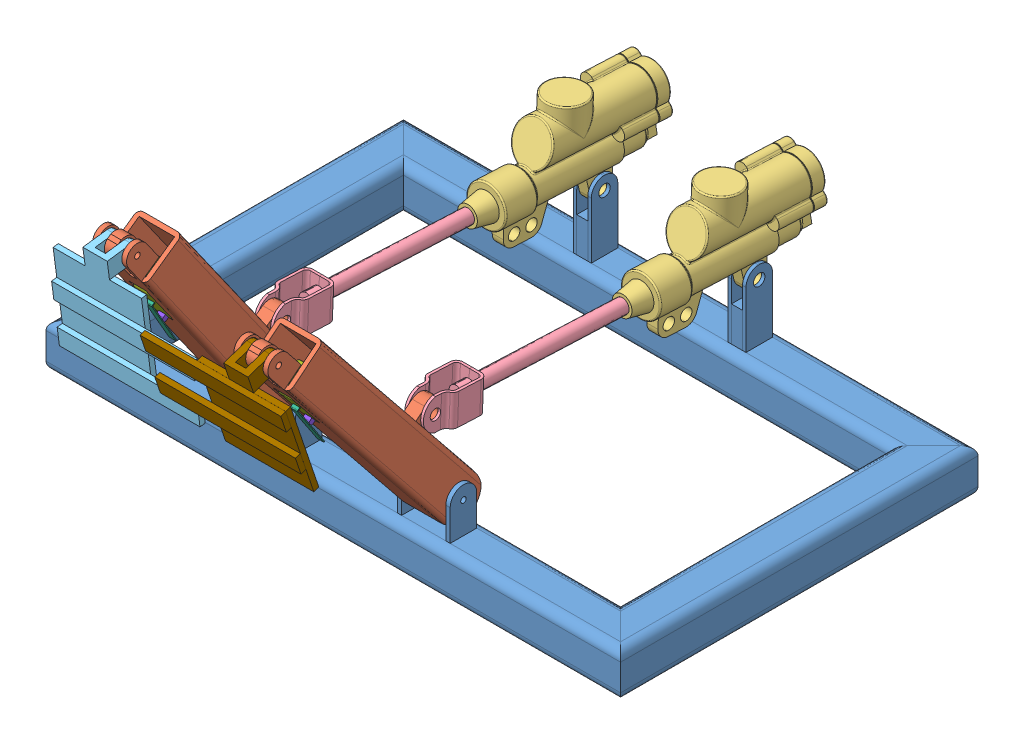
SolidWorks assembly full braking system, configuration Default. Lengths in mm.
Overall size (330.2 3165.35 520.81).
17 component instances, 9 part files, 15 mates.
Components (placement in the parent):
- brake system base-1: brake system base [Default<As Machined>] at (-94.6007 148.0737 400.8899) size (330.2 65.4 205.4)
- brake pedal arm-1: brake pedal arm [Default] at (117.4015 176.6408 383.0316) x (-1 0 0) z (0 0.627773 -0.778397) size (25.4 171.45 40.13)
- brake pedal arm-2: brake pedal arm [Default] at (28.5015 175.4821 383.194) x (-1 0 0) z (0 0.57576 -0.817619) size (25.4 171.45 40.13)
- brake cylinder body-1: brake cylinder body [Default] at (104.7015 212.0557 239.8642) x (-1 0 0) z (0 -0.999069 0.043148) size (26.15 339.45 1611.72)
- brake cylinder arm-1: brake cylinder arm [Default] at (104.7015 214.0337 285.6647) x (-1 0 0) z (0 -0.999069 0.043148) size (17.78 341.55 1584.44)
- brake cylinder arm-2: brake cylinder arm [Default] at (15.8015 214.0679 283.0124) x (1 0 0) z (0 0.998964 -0.045505) size (17.78 341.55 1584.44)
- brake cylinder body-2: brake cylinder body [Default] at (15.8015 212.1004 239.8196) x (-1 0 0) z (0 -0.998964 0.045505) size (26.15 339.45 1611.72)
- foot pedal-1: foot pedal [Default] at (41.2378 242.3659 500.6466) x (-1 0 0) z (0 -0.99155 -0.129724) size (80.8 22.05 60.82)
- micro switch-1: micro switch [Predeterminado] at (41.8342 255.3389 462.4174) x (0 -0.918933 -0.394414) z (-1 0 0) size (51.53 26.23 10)
  - palanca switch-1: palanca switch [Predeterminado] at (152.408 -13.1757 63.6721) x (0.993061 -0.117596 0) z (0 0 1) size (28 5 6)
  - switch-1: switch [Predeterminado] at (-58.9157 -3.0205 31.2303) x (-0.978425 0.206604 0) z (-0.206604 -0.978425 0) size (37 10 19)
  - boton-1: boton [Predeterminado] at (0.7172 5.2123 24.2303) x (-0.978425 0.206604 0) z (0 0 -1) size (3 4 4)
- micro switch-2: micro switch [Predeterminado] at (130.7342 251.1699 467.2863) x (0 -0.891303 -0.453409) z (-1 0 0) size (51.53 26.23 10)
  - palanca switch-1: palanca switch [Predeterminado] at (152.408 -13.1757 63.6721) x (0.993061 -0.117596 0) z (0 0 1) size (28 5 6)
  - switch-1: switch [Predeterminado] at (-58.9157 -3.0205 31.2303) x (-0.978425 0.206604 0) z (-0.206604 -0.978425 0) size (37 10 19)
  - boton-1: boton [Predeterminado] at (0.7172 5.2123 24.2303) x (-0.978425 0.206604 0) z (0 0 -1) size (3 4 4)
- foot pedal 2-1: foot pedal 2 [Default] at (130.1378 235.8403 497.094) x (-1 0 0) z (0 -0.94746 -0.319874) size (80.86 22.05 60.82)
Mates (geometry in assembly coordinates):
- Coincident1: coincident: circle of brake system base-1; circle of brake pedal arm-2
- Coincident2: coincident: circle of brake system base-1; circle of brake pedal arm-2
- Coincident3: coincident: circle of brake system base-1; circle of brake pedal arm-1
- Concentric2: concentric anti-aligned: circle of brake cylinder body-1; circle of brake cylinder arm-1
- Coincident8: coincident anti-aligned: circle of brake pedal arm-1; circle of brake cylinder arm-1
- Coincident12: coincident aligned: circle of brake pedal arm-2; circle of brake cylinder arm-2
- Concentric12: concentric anti-aligned: circle of brake cylinder arm-2; circle of brake cylinder body-2
- Coincident13: coincident aligned: circle of brake pedal arm-2; circle of foot pedal-1
- Coincident14: coincident aligned: circle of brake pedal arm-1; circle of foot pedal 2-1
- Coincident15: coincident anti-aligned: line of brake pedal arm-1 through (109.5039 247.3163 472.6621) axis (0 0.778397 0.627773); line of micro switch-2/switch-1 through (109.5039 264.441 486.4731) axis (0 -0.778397 -0.627773)
- Coincident16: coincident anti-aligned: line of brake pedal arm-1 through (99.5039 247.3163 472.6621) axis (1 0 0); line of micro switch-2/switch-1 through (109.5039 247.3163 472.6621) axis (-1 0 0)
- Coincident17: coincident anti-aligned: line of brake pedal arm-2 through (20.6039 251.8435 468.0328) axis (0 0.817619 0.57576); line of micro switch-1/switch-1 through (20.6039 269.8311 480.6995) axis (0 -0.817619 -0.57576)
- Coincident19: coincident anti-aligned: line of brake pedal arm-2 through (10.6039 251.8435 468.0328) axis (1 0 0); line of micro switch-1/switch-1 through (20.6039 251.8435 468.0328) axis (-1 0 0)
- Concentric13: concentric aligned: circle of brake system base-1; circle of brake cylinder body-1
- Concentric14: concentric anti-aligned: cylinder of brake system base-1 through (-107.3007 193.1697 220.8899) axis (1 0 0) radius 3.295; circle of brake cylinder body-2
